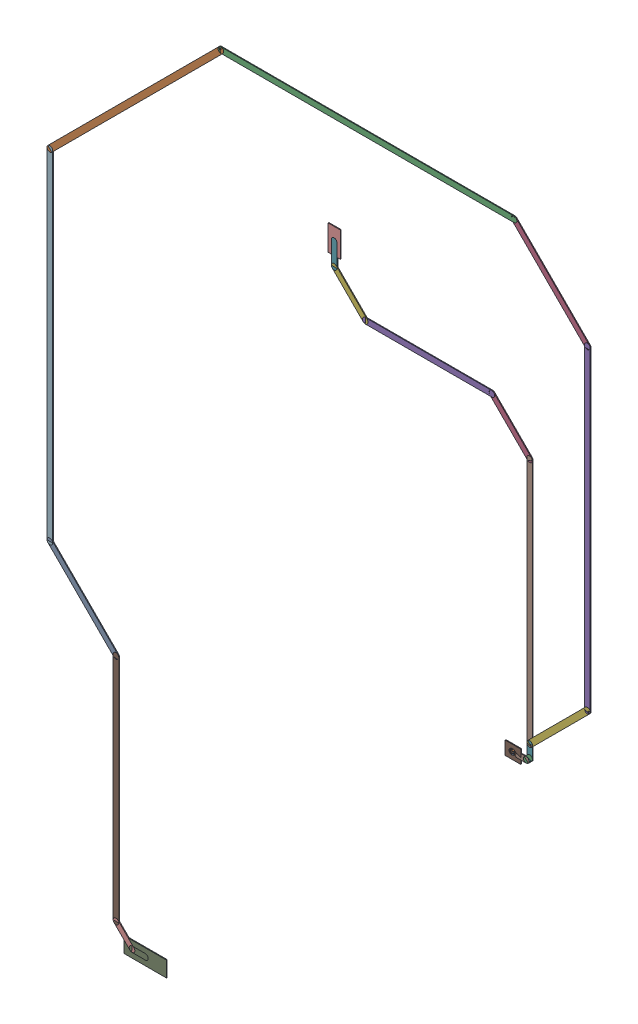
SolidWorks assembly SDA, configuration Predeterminado. Lengths in mm.
Overall size (24.45 37.53 0.04).
69 component instances, 23 part files, 0 mates.
Components (placement in the parent):
- Track (31mm,40mm)(31mm,40mm) on Top Layer-1: Track (31mm,40mm)(31mm,40mm) on Top Layer [Predeterminado] at origin size (0.25 0.25 0.04)
  - Track (31mm,40mm)(31mm,40mm) on Top Layer-1-1: Track (31mm,40mm)(31mm,40mm) on Top Layer-1 [Predeterminado] at (-68.317 -44.187 -0.0457) size (0.25 0.25 0.04)
    - Track (31mm,40mm)(31mm,40mm) on Top Layer-Part-1-1: Track (31mm,40mm)(31mm,40mm) on Top Layer-Part-1 [Predeterminado] at origin size (0.25 0.25 0.04)
- Track (31mm,40mm)(31.05mm,40mm) on Top Layer-1: Track (31mm,40mm)(31.05mm,40mm) on Top Layer [Predeterminado] at origin size (0.3 0.25 0.04)
  - Track (31mm,40mm)(31.05mm,40mm) on Top Layer-1-1: Track (31mm,40mm)(31.05mm,40mm) on Top Layer-1 [Predeterminado] at (-68.317 -44.187 -0.0457) size (0.3 0.25 0.04)
    - Track (31mm,40mm)(31.05mm,40mm) on Top Layer-Part-1-1: Track (31mm,40mm)(31.05mm,40mm) on Top Layer-Part-1 [Predeterminado] at origin size (0.3 0.25 0.04)
- Track (31.65mm,40mm)(31.8mm,40.15mm) on Top Layer-1: Track (31.65mm,40mm)(31.8mm,40.15mm) on Top Layer [Predeterminado] at origin size (0.4 0.4 0.04)
  - Track (31.65mm,40mm)(31.8mm,40.15mm) on Top Layer-1-1: Track (31.65mm,40mm)(31.8mm,40.15mm) on Top Layer-1 [Predeterminado] at (-68.317 -44.187 -0.0457) size (0.4 0.4 0.04)
    - Track (31.65mm,40mm)(31.8mm,40.15mm) on Top Layer-Part-1-1: Track (31.65mm,40mm)(31.8mm,40.15mm) on Top Layer-Part-1 [Predeterminado] at origin size (0.4 0.4 0.04)
- Track (30.1mm,53.5mm)(31.8mm,51.8mm) on Top Layer-1: Track (30.1mm,53.5mm)(31.8mm,51.8mm) on Top Layer [Predeterminado] at origin size (1.95 1.95 0.04)
  - Track (30.1mm,53.5mm)(31.8mm,51.8mm) on Top Layer-1-1: Track (30.1mm,53.5mm)(31.8mm,51.8mm) on Top Layer-1 [Predeterminado] at (-68.317 -44.187 -0.0457) size (1.95 1.95 0.04)
    - Track (30.1mm,53.5mm)(31.8mm,51.8mm) on Top Layer-Part-1-1: Track (30.1mm,53.5mm)(31.8mm,51.8mm) on Top Layer-Part-1 [Predeterminado] at origin size (1.95 1.95 0.04)
- Track (24.4mm,53.5mm)(30.1mm,53.5mm) on Top Layer-1: Track (24.4mm,53.5mm)(30.1mm,53.5mm) on Top Layer [Predeterminado] at origin size (5.95 0.25 0.04)
  - Track (24.4mm,53.5mm)(30.1mm,53.5mm) on Top Layer-1-1: Track (24.4mm,53.5mm)(30.1mm,53.5mm) on Top Layer-1 [Predeterminado] at (-68.317 -44.187 -0.0457) size (5.95 0.25 0.04)
    - Track (24.4mm,53.5mm)(30.1mm,53.5mm) on Top Layer-Part-1-1: Track (24.4mm,53.5mm)(30.1mm,53.5mm) on Top Layer-Part-1 [Predeterminado] at origin size (5.95 0.25 0.04)
- Track (23mm,54.9mm)(24.4mm,53.5mm) on Top Layer-1: Track (23mm,54.9mm)(24.4mm,53.5mm) on Top Layer [Predeterminado] at origin size (1.65 1.65 0.04)
  - Track (23mm,54.9mm)(24.4mm,53.5mm) on Top Layer-1-1: Track (23mm,54.9mm)(24.4mm,53.5mm) on Top Layer-1 [Predeterminado] at (-68.317 -44.187 -0.0457) size (1.65 1.65 0.04)
    - Track (23mm,54.9mm)(24.4mm,53.5mm) on Top Layer-Part-1-1: Track (23mm,54.9mm)(24.4mm,53.5mm) on Top Layer-Part-1 [Predeterminado] at origin size (1.65 1.65 0.04)
- Track (23mm,54.9mm)(23mm,55.903mm) on Top Layer-1: Track (23mm,54.9mm)(23mm,55.903mm) on Top Layer [Predeterminado] at origin size (0.25 1.26 0.04)
  - Track (23mm,54.9mm)(23mm,55.903mm) on Top Layer-1-1: Track (23mm,54.9mm)(23mm,55.903mm) on Top Layer-1 [Predeterminado] at (-68.317 -44.187 -0.0457) size (0.25 1.26 0.04)
    - Track (23mm,54.9mm)(23mm,55.903mm) on Top Layer-Part-1-1: Track (23mm,54.9mm)(23mm,55.903mm) on Top Layer-Part-1 [Predeterminado] at origin size (0.25 1.26 0.04)
- Track (31mm,40mm)(31.65mm,40mm) on Top Layer-1: Track (31mm,40mm)(31.65mm,40mm) on Top Layer [Predeterminado] at origin size (0.9 0.25 0.04)
  - Track (31mm,40mm)(31.65mm,40mm) on Top Layer-1-1: Track (31mm,40mm)(31.65mm,40mm) on Top Layer-1 [Predeterminado] at (-68.317 -44.187 -0.0457) size (0.9 0.25 0.04)
    - Track (31mm,40mm)(31.65mm,40mm) on Top Layer-Part-1-1: Track (31mm,40mm)(31.65mm,40mm) on Top Layer-Part-1 [Predeterminado] at origin size (0.9 0.25 0.04)
- Track (13.9mm,23.75mm)(14.5mm,23.75mm) on Top Layer-1: Track (13.9mm,23.75mm)(14.5mm,23.75mm) on Top Layer [Predeterminado] at origin size (0.85 0.25 0.04)
  - Track (13.9mm,23.75mm)(14.5mm,23.75mm) on Top Layer-1-1: Track (13.9mm,23.75mm)(14.5mm,23.75mm) on Top Layer-1 [Predeterminado] at (-68.317 -44.187 -0.0457) size (0.85 0.25 0.04)
    - Track (13.9mm,23.75mm)(14.5mm,23.75mm) on Top Layer-Part-1-1: Track (13.9mm,23.75mm)(14.5mm,23.75mm) on Top Layer-Part-1 [Predeterminado] at origin size (0.85 0.25 0.04)
- Track (13.178mm,24.472mm)(13.9mm,23.75mm) on Top Layer-1: Track (13.178mm,24.472mm)(13.9mm,23.75mm) on Top Layer [Predeterminado] at origin size (0.98 0.98 0.04)
  - Track (13.178mm,24.472mm)(13.9mm,23.75mm) on Top Layer-1-1: Track (13.178mm,24.472mm)(13.9mm,23.75mm) on Top Layer-1 [Predeterminado] at (-68.317 -44.187 -0.0457) size (0.98 0.98 0.04)
    - Track (13.178mm,24.472mm)(13.9mm,23.75mm) on Top Layer-Part-1-1: Track (13.178mm,24.472mm)(13.9mm,23.75mm) on Top Layer-Part-1 [Predeterminado] at origin size (0.98 0.98 0.04)
- Track (13.178mm,24.472mm)(13.178mm,34.822mm) on Top Layer-1: Track (13.178mm,24.472mm)(13.178mm,34.822mm) on Top Layer [Predeterminado] at origin size (0.25 10.6 0.04)
  - Track (13.178mm,24.472mm)(13.178mm,34.822mm) on Top Layer-1-1: Track (13.178mm,24.472mm)(13.178mm,34.822mm) on Top Layer-1 [Predeterminado] at (-68.317 -44.187 -0.0457) size (0.25 10.6 0.04)
    - Track (13.178mm,24.472mm)(13.178mm,34.822mm) on Top Layer-Part-1-1: Track (13.178mm,24.472mm)(13.178mm,34.822mm) on Top Layer-Part-1 [Predeterminado] at origin size (0.25 10.6 0.04)
- Track (10.2mm,37.8mm)(10.2mm,53.1mm) on Top Layer-1: Track (10.2mm,37.8mm)(10.2mm,53.1mm) on Top Layer [Predeterminado] at origin size (0.25 15.55 0.04)
  - Track (10.2mm,37.8mm)(10.2mm,53.1mm) on Top Layer-1-1: Track (10.2mm,37.8mm)(10.2mm,53.1mm) on Top Layer-1 [Predeterminado] at (-68.317 -44.187 -0.0457) size (0.25 15.55 0.04)
    - Track (10.2mm,37.8mm)(10.2mm,53.1mm) on Top Layer-Part-1-1: Track (10.2mm,37.8mm)(10.2mm,53.1mm) on Top Layer-Part-1 [Predeterminado] at origin size (0.25 15.55 0.04)
- Track (10.2mm,37.8mm)(13.178mm,34.822mm) on Top Layer-1: Track (10.2mm,37.8mm)(13.178mm,34.822mm) on Top Layer [Predeterminado] at origin size (3.23 3.23 0.04)
  - Track (10.2mm,37.8mm)(13.178mm,34.822mm) on Top Layer-1-1: Track (10.2mm,37.8mm)(13.178mm,34.822mm) on Top Layer-1 [Predeterminado] at (-68.317 -44.187 -0.0457) size (3.23 3.23 0.04)
    - Track (10.2mm,37.8mm)(13.178mm,34.822mm) on Top Layer-Part-1-1: Track (10.2mm,37.8mm)(13.178mm,34.822mm) on Top Layer-Part-1 [Predeterminado] at origin size (3.23 3.23 0.04)
- Track (10.2mm,53.1mm)(17.9mm,60.8mm) on Top Layer-1: Track (10.2mm,53.1mm)(17.9mm,60.8mm) on Top Layer [Predeterminado] at origin size (7.95 7.95 0.04)
  - Track (10.2mm,53.1mm)(17.9mm,60.8mm) on Top Layer-1-1: Track (10.2mm,53.1mm)(17.9mm,60.8mm) on Top Layer-1 [Predeterminado] at (-68.317 -44.187 -0.0457) size (7.95 7.95 0.04)
    - Track (10.2mm,53.1mm)(17.9mm,60.8mm) on Top Layer-Part-1-1: Track (10.2mm,53.1mm)(17.9mm,60.8mm) on Top Layer-Part-1 [Predeterminado] at origin size (7.95 7.95 0.04)
- Track (17.9mm,60.8mm)(31.1mm,60.8mm) on Top Layer-1: Track (17.9mm,60.8mm)(31.1mm,60.8mm) on Top Layer [Predeterminado] at origin size (13.45 0.25 0.04)
  - Track (17.9mm,60.8mm)(31.1mm,60.8mm) on Top Layer-1-1: Track (17.9mm,60.8mm)(31.1mm,60.8mm) on Top Layer-1 [Predeterminado] at (-68.317 -44.187 -0.0457) size (13.45 0.25 0.04)
    - Track (17.9mm,60.8mm)(31.1mm,60.8mm) on Top Layer-Part-1-1: Track (17.9mm,60.8mm)(31.1mm,60.8mm) on Top Layer-Part-1 [Predeterminado] at origin size (13.45 0.25 0.04)
- Track (31.1mm,60.8mm)(34.4mm,57.5mm) on Top Layer-1: Track (31.1mm,60.8mm)(34.4mm,57.5mm) on Top Layer [Predeterminado] at origin size (3.55 3.55 0.04)
  - Track (31.1mm,60.8mm)(34.4mm,57.5mm) on Top Layer-1-1: Track (31.1mm,60.8mm)(34.4mm,57.5mm) on Top Layer-1 [Predeterminado] at (-68.317 -44.187 -0.0457) size (3.55 3.55 0.04)
    - Track (31.1mm,60.8mm)(34.4mm,57.5mm) on Top Layer-Part-1-1: Track (31.1mm,60.8mm)(34.4mm,57.5mm) on Top Layer-Part-1 [Predeterminado] at origin size (3.55 3.55 0.04)
- Track (34.4mm,43.3mm)(34.4mm,57.5mm) on Top Layer-1: Track (34.4mm,43.3mm)(34.4mm,57.5mm) on Top Layer [Predeterminado] at origin size (0.25 14.45 0.04)
  - Track (34.4mm,43.3mm)(34.4mm,57.5mm) on Top Layer-1-1: Track (34.4mm,43.3mm)(34.4mm,57.5mm) on Top Layer-1 [Predeterminado] at (-68.317 -44.187 -0.0457) size (0.25 14.45 0.04)
    - Track (34.4mm,43.3mm)(34.4mm,57.5mm) on Top Layer-Part-1-1: Track (34.4mm,43.3mm)(34.4mm,57.5mm) on Top Layer-Part-1 [Predeterminado] at origin size (0.25 14.45 0.04)
- Track (31.8mm,40.7mm)(34.4mm,43.3mm) on Top Layer-1: Track (31.8mm,40.7mm)(34.4mm,43.3mm) on Top Layer [Predeterminado] at origin size (2.85 2.85 0.04)
  - Track (31.8mm,40.7mm)(34.4mm,43.3mm) on Top Layer-1-1: Track (31.8mm,40.7mm)(34.4mm,43.3mm) on Top Layer-1 [Predeterminado] at (-68.317 -44.187 -0.0457) size (2.85 2.85 0.04)
    - Track (31.8mm,40.7mm)(34.4mm,43.3mm) on Top Layer-Part-1-1: Track (31.8mm,40.7mm)(34.4mm,43.3mm) on Top Layer-Part-1 [Predeterminado] at origin size (2.85 2.85 0.04)
- Track (31.8mm,40.15mm)(31.8mm,40.7mm) on Top Layer-1: Track (31.8mm,40.15mm)(31.8mm,40.7mm) on Top Layer [Predeterminado] at origin size (0.25 0.8 0.04)
  - Track (31.8mm,40.15mm)(31.8mm,40.7mm) on Top Layer-1-1: Track (31.8mm,40.15mm)(31.8mm,40.7mm) on Top Layer-1 [Predeterminado] at (-68.317 -44.187 -0.0457) size (0.25 0.8 0.04)
    - Track (31.8mm,40.15mm)(31.8mm,40.7mm) on Top Layer-Part-1-1: Track (31.8mm,40.15mm)(31.8mm,40.7mm) on Top Layer-Part-1 [Predeterminado] at origin size (0.25 0.8 0.04)
- Track (31.8mm,40.7mm)(31.8mm,51.8mm) on Top Layer-1: Track (31.8mm,40.7mm)(31.8mm,51.8mm) on Top Layer [Predeterminado] at origin size (0.25 11.35 0.04)
  - Track (31.8mm,40.7mm)(31.8mm,51.8mm) on Top Layer-1-1: Track (31.8mm,40.7mm)(31.8mm,51.8mm) on Top Layer-1 [Predeterminado] at (-68.317 -44.187 -0.0457) size (0.25 11.35 0.04)
    - Track (31.8mm,40.7mm)(31.8mm,51.8mm) on Top Layer-Part-1-1: Track (31.8mm,40.7mm)(31.8mm,51.8mm) on Top Layer-Part-1 [Predeterminado] at origin size (0.25 11.35 0.04)
- Pad RAK4600-4(14.5mm,23.75mm) on Top Layer-1: Pad RAK4600-4(14.5mm,23.75mm) on Top Layer [Predeterminado] at origin size (1.9 0.7 0.04)
  - Pad RAK4600-4(14.5mm,23.75mm) on Top Layer-1-1: Pad RAK4600-4(14.5mm,23.75mm) on Top Layer-1 [Predeterminado] at (-68.317 -44.187 -0.0457) size (1.9 0.7 0.04)
    - Pad RAK4600-4(14.5mm,23.75mm) on Top Layer-Part-1-1: Pad RAK4600-4(14.5mm,23.75mm) on Top Layer-Part-1 [Predeterminado] at origin size (1.9 0.7 0.04)
- Pad ADXL345-13(23mm,55.903mm) on Top Layer-1: Pad ADXL345-13(23mm,55.903mm) on Top Layer [Predeterminado] at origin size (0.55 1.15 0.04)
  - Pad ADXL345-13(23mm,55.903mm) on Top Layer-1-1: Pad ADXL345-13(23mm,55.903mm) on Top Layer-1 [Predeterminado] at (-68.317 -44.187 -0.0457) size (0.55 1.15 0.04)
    - Pad ADXL345-13(23mm,55.903mm) on Top Layer-Part-1-1: Pad ADXL345-13(23mm,55.903mm) on Top Layer-Part-1 [Predeterminado] at origin size (0.55 1.15 0.04)
- Pad R2-1(31.05mm,40mm) on Top Layer-1: Pad R2-1(31.05mm,40mm) on Top Layer [Predeterminado] at origin size (0.7 0.6 0.04)
  - Pad R2-1(31.05mm,40mm) on Top Layer-1-1: Pad R2-1(31.05mm,40mm) on Top Layer-1 [Predeterminado] at (-68.317 -44.187 -0.0457) size (0.7 0.6 0.04)
    - Pad R2-1(31.05mm,40mm) on Top Layer-Part-1-1: Pad R2-1(31.05mm,40mm) on Top Layer-Part-1 [Predeterminado] at origin size (0.7 0.6 0.04)
